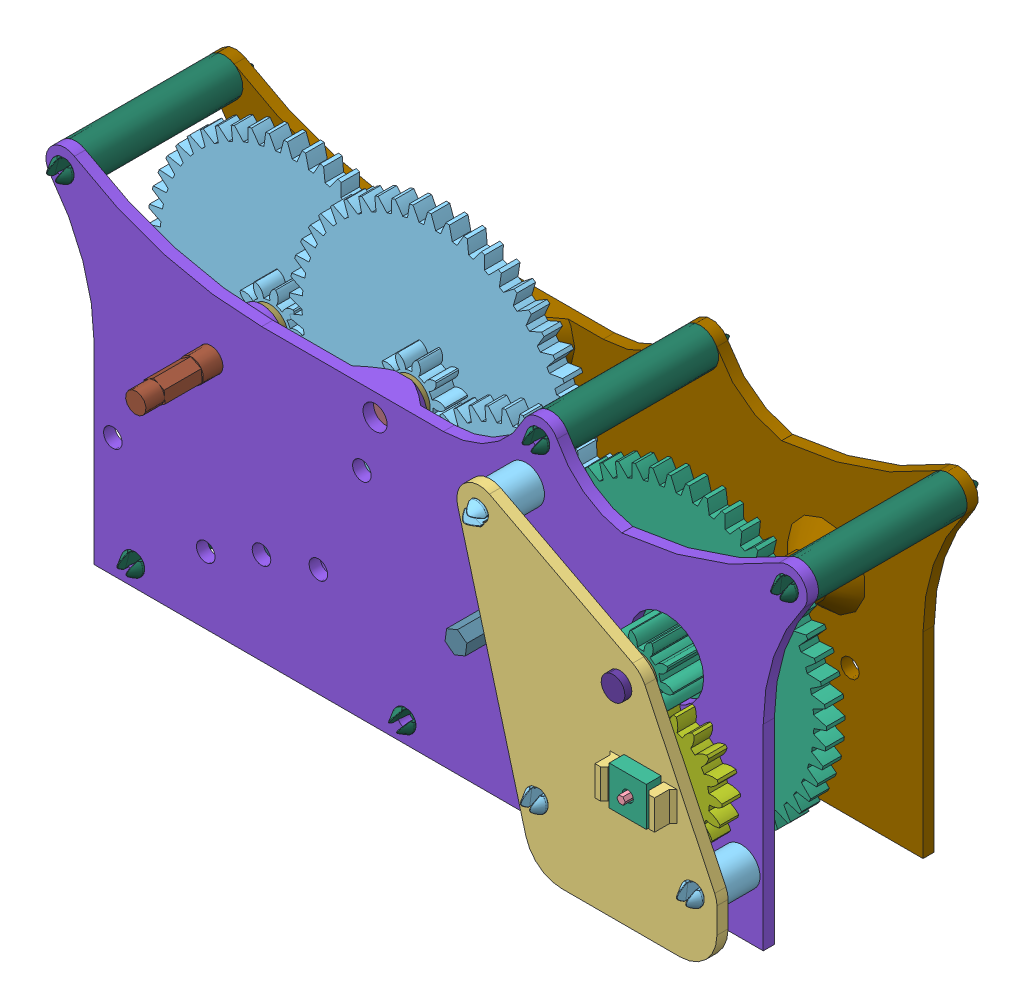
SolidWorks assembly gear_box_asm, configuration Default. Lengths in mm.
Overall size (222.79 131.64 101.4).
40 component instances, 24 part files, 110 mates.
Components (placement in the parent):
- motor_engagement-1: motor_engagement [Default] x (0.299774 -0.95401 0) z (0 0 1) size (23 23 4)
- engagement_adapter-1: engagement_adapter [Default] at (0 0 5) x (-0.299774 0.95401 0) z (-0.95401 -0.299774 0) size (25 21 25)
- metric_gear_10_hex-3: metric_gear_10_hex [Metric - Spur gear 1.5M 10T 20PA 12FW ---S10N75H50L5N] at (0 0 9) x (0 0 1) z (0.67631 0.736617 0) size (5 17.23 18)
- metric_gear_30_hex-2: metric_gear_30_hex [Metric - Spur gear 1.5M 33T 20PA 5FW ---S33N75H50L5N] at (30.3051 11.0301 14) x (0 0 -1) z (0.924711 -0.380669 0) size (11 52.42 52.48)
- metric_gear_50_hex-4: metric_gear_50_hex [Metric - Spur gear 1.5M 50T 20PA 5FW ---S50N75H50L5N] at (1.3796 45.5021 20) x (0 0 -1) z (-0.438763 -0.898603 0) size (11 77.9 78)
- metric_gear_50_hex-6: metric_gear_50_hex [Metric - Spur gear 1.5M 50T 20PA 5FW ---S50N75H50L5N] at (45.5529 54.0886 26) x (0 0 -1) z (-0.450414 -0.89282 0) size (11 77.9 78)
- metric_gear_50_hex-7: metric_gear_50_hex [Metric - Spur gear 1.5M 50T 20PA 5FW ---S50N75H50L5N] at (80.5244 25.7691 32) x (0 0 -1) z (-0.383635 0.923485 0) size (11 77.9 78)
- metric_gear_50_hex_extralong-7: metric_gear_50_hex_extralong [Metric - Spur gear 1.5M 50T 20PA 5FW ---S50N75H50L5N] at (123.9911 37.416 38) x (0 0 -1) z (0.962925 0.269769 0) size (16.2 77.9 78)
- metric_gear_19_hex-8: metric_gear_19_hex [Metric - Spur gear 1.5M 19T 20PA 5FW ---S19N75H50L5N] at (130.3502 16.6164 49.2) x (0 0 -1) z (-0.050856 0.998706 0) size (5 31.34 31.45)
- back_side-1: back_side [Default] at (0 0 39) size (204.87 94.29 19.7)
- front_side-2: front_side [Default] at (0 0 -4) size (204.87 94.29 34.7)
- engagement_support-1: engagement_support [Default] at (0 0 15) size (36.78 28.08 3)
- long_axle-1: long_axle [Default] at (1.3796 45.5021 7.8) x (-0.829281 -0.558831 0) z (0 0 1) size (10 10 54.4)
- small_washer-1: small_washer [Default] at (1.3796 45.5021 26.2) size (10 10 2)
- small_axle-2: small_axle [Default] at (45.5529 54.0886 13.8) x (0.567604 -0.823302 0) z (0 0 1) size (10 10 25.4)
- small_washer-2: small_washer [Default] at (45.5529 54.0886 34.2) x (-0.878181 -0.478329 0) z (0 0 -1) size (10 10 2)
- fourth_stage_axle-1: fourth_stage_axle [Default] at (80.5244 25.7691 19.8) x (-0.79398 0.607944 0) z (0 0 1) size (10 10 35.4)
- small_axle-4: small_axle [Default] at (30.3051 11.0301 1.8) x (0.792025 0.610489 0) z (0 0 1) size (10 10 25.4)
- small_washer-4: small_washer [Default] at (30.3051 11.0301 20.2) x (0.994715 0.102676 0) z (0 0 1) size (10 10 2)
- snap_fastner-1: snap_fastner [Default] at (156.8716 70.2965 -1) x (0 0 -1) z (0.991152 -0.132733 0) size (53.67 10 10)
- snap_fastner-2: snap_fastner [Default] at (90 71.2935 -1) x (0 0 -1) z (0.953456 -0.301532 0) size (53.67 10 10)
- snap_fastner-3: snap_fastner [Default] at (-38 70.2305 -1) x (0 0 -1) z (0.96799 -0.250988 0) size (53.67 10 10)
- snap_fastner-4: snap_fastner [Default] at (-19 -12 -1) x (0 0 -1) z (0.96799 -0.250988 0) size (53.67 10 10)
- snap_fastner-5: snap_fastner [Default] at (54 -12 -1) x (0 0 -1) z (0.853652 -0.520844 0) size (53.67 10 10)
- snap_fastner-6: snap_fastner [Default] at (116 -12 -1) x (0 0 -1) z (0.853652 -0.520844 0) size (53.67 10 10)
- snap_fastner_short-1: snap_fastner_short [Default] at (-17.3843 6.3274 -1) x (0 0 -1) z (0.97154 0.236875 0) size (29.67 7.5 7.5)
- snap_fastner_short-2: snap_fastner_short [Default] at (11.8916 -14.1718 -1) x (0 0 -1) z (0.935775 0.352597 0) size (29.67 7.5 7.5)
- fifth_stage_axle-1: fifth_stage_axle [Default] at (123.9911 37.416 25.8) x (0.968802 -0.247836 0) z (0 0 1) size (10 10 30.6)
- motor-1: motor [Default] at (0 0 -6) x (0 1 0) z (0 0 -1) size (24 18 42)
- motor_support-1: motor_support [Default] at (0 -12 -36.2) size (39.4 22 35.2)
- snap_fastner_motor-1: snap_fastner_motor [Default] at (-16.2 -2 -10) x (0 0 -1) z (0.97154 0.236875 0) size (19.67 7.5 7.5)
- snap_fastner_motor-2: snap_fastner_motor [Default] at (16.2 -2 -10) x (0 0 -1) z (0.999999 -0.001115 0) size (19.67 7.5 7.5)
- output_support-1: output_support [Default] at (144.1487 -1.1316 51.6) size (70 82.87 8)
- pot_axle-1: pot_axle [Default] at (130.3502 16.6164 39) x (0.543396 -0.839477 0) z (0 0 1) size (10 10 21.6)
- small_washer-5: small_washer [Default] at (123.9911 37.416 51.4) x (-0.878181 -0.478329 0) z (0 0 -1) size (10 10 2)
- small_washer-6: small_washer [Default] at (130.3502 16.6164 51.4) x (-0.878181 -0.478329 0) z (0 0 -1) size (10 10 2)
- output_snap_fastner-1: output_snap_fastner [Default] at (144.1487 -1.1316 42) x (0 0 -1) z (0.99268 -0.120771 0) size (23.27 10 10)
- output_snap_fastner-2: output_snap_fastner [Default] at (102.1487 -0.2026 42) x (0 0 -1) z (0.99268 -0.120771 0) size (23.27 10 10)
- output_snap_fastner-3: output_snap_fastner [Default] at (86.1487 58.8684 42) x (0 0 -1) z (0.438758 0.898605 0) size (23.27 10 10)
- pot_simplified-1: pot_simplified [Default] at (125.3502 11.3664 54.8) x (1 0 0) z (0 -1 0) size (10 4 10.5)
Mates (geometry in assembly coordinates):
- Coincident1: coincident anti-aligned: plane of motor_engagement-1 through (0 0 0) normal (0 0 -1)
- Concentric2: concentric: cylinder of motor_engagement-1 through (0 0 0) axis (0 0 1) radius 2
- Concentric3: concentric anti-aligned: cylinder of motor_engagement-1 through (0 0 4) axis (0 0 -1) radius 11.5; cylinder of engagement_adapter-1 through (0 0 4) axis (0 0 1) radius 12.5
- Parallel1: parallel aligned: plane of motor_engagement-1 through (4.6475 3.5568 4) normal (0.95401 0.299774 0); plane of engagement_adapter-1 through (9.6 0.9725 -2) normal (0.95401 0.299774 0)
- Parallel2: parallel anti-aligned: plane of engagement_adapter-1 through (0 0 6) normal (0 0 1); plane of metric_gear_10_hex-3 through (0 0 7) normal (0 0 -1)
- Coincident3: coincident aligned: plane of metric_gear_10_hex-3 through (0 0 14) normal (0 0 1); plane of metric_gear_30_hex-2 through (30.3051 11.0301 14) normal (0 0 1)
- Parallel3: parallel anti-aligned: plane of engagement_adapter-1 through (-3.5298 -1.1092 13) normal (-0.67631 -0.736617 0); plane of metric_gear_10_hex-3 through (-3.5775 -1.1242 59.0003) normal (0.67631 0.736617 0)
- Parallel4: parallel anti-aligned: plane of engagement_adapter-1 through (-0.8044 -3.6115 13) normal (0.299774 -0.95401 0); plane of metric_gear_10_hex-3 through (-0.8152 -3.6603 59.0003) normal (-0.299774 0.95401 0)
- Concentric4: concentric anti-aligned: cylinder of engagement_adapter-1 through (0 0 4) axis (0 0 1) radius 12.5; circle of metric_gear_10_hex-1
- Concentric5: concentric aligned: circle of metric_gear_30_hex-1
- Coincident5: coincident anti-aligned: plane of motor_engagement-1 through (0 0 4) normal (0 0 1); plane of engagement_adapter-1 through (0 0 4) normal (0 0 -1)
- GearMate2: gear = 33 : 10 mm: circle of metric_gear_10_hex-1; circle of metric_gear_30_hex-1
- Concentric6: concentric anti-aligned: circle of metric_gear_30_hex-1; cylinder of metric_gear_50_hex-5 through (30.3051 11.0301 35.6013) axis (0 0 -1) radius 35.624
- Coincident6: coincident aligned: plane of metric_gear_30_hex-2 through (27.335 8.7408 -36.0001) normal (0.991158 0.132687 0); plane of metric_gear_50_hex-5 through (32.278 12.5656 80.6014) normal (-0.37634 -0.926481 0)
- Coincident7: coincident aligned: plane of metric_gear_30_hex-2 through (28.1536 8.2393 20) normal (0 0 1); plane of metric_gear_50_hex-4 through (1.3796 45.5021 20) normal (0 0 1)
- Concentric7: concentric aligned: circle of spur gear_am-4
- GearMate3: gear = 10 : 50 mm: circle of spur gear_am-4; circle of metric_gear_30_hex-1
- Coincident8: coincident aligned: plane of metric_gear_50_hex-4 through (-1.2686 47.8269 26) normal (0 0 1); plane of metric_gear_50_hex-6 through (45.5529 54.0886 26) normal (0 0 1)
- Concentric8: concentric aligned: circle of metric_gear_50_hex-2
- GearMate4: gear = 10 : 50 mm: circle of metric_gear_50_hex-2; circle of metric_gear_50_hex-1
- Concentric9: concentric aligned: circle of metric_gear_50_hex-3
- Coincident9: coincident aligned: plane of metric_gear_50_hex-6 through (42.9351 56.4476 32) normal (0 0 1); plane of metric_gear_50_hex-7 through (80.5244 25.7691 32) normal (0 0 1)
- GearMate5: gear = 10 : 50 mm: circle of metric_gear_50_hex-3; circle of metric_gear_50_hex-2
- Coincident10: coincident aligned: plane of metric_gear_50_hex-7 through (84.0197 26.2172 38) normal (0 0 1); plane of metric_gear_50_hex_extralong-7 through (123.9911 37.416 38) normal (0 0 1)
- Concentric10: concentric aligned: circle of metric_gear_50_hex-4
- GearMate6: gear = 50 : 10 mm: circle of metric_gear_50_hex-3; circle of metric_gear_50_hex-4
- Concentric11: concentric aligned: circle of spur gear_am-5
- Concentric12: concentric anti-aligned: cylinder of engagement_adapter-1 through (0 0 4) axis (0 0 1) radius 12.5; cylinder of back_side-1 through (0 0 42) axis (0 0 -1) radius 2.5
- Parallel5: parallel aligned: plane of back_side-1 through (0 0 39) normal (0 1 0)
- Distance1: distance = 1 mm anti-aligned: plane of metric_gear_50_hex_extralong-7 through (123.9911 37.416 38) normal (0 0 1); plane of back_side-1 through (0 0 39) normal (0 0 -1)
- Coincident11: coincident aligned: plane of metric_gear_50_hex_extralong-7 through (124.0155 33.8922 49.2) normal (0 0 1); plane of metric_gear_19_hex-8 through (130.3502 16.6164 49.2) normal (0 0 1)
- GearMate7: gear = 19 : 10 mm: circle of metric_gear_50_hex_extralong-1; circle of metric_gear_19_hex-1
- Parallel6: parallel anti-aligned: plane of back_side-1 through (0 0 39) normal (0 0 -1); plane of front_side-2 through (0 0 -1) normal (0 0 1)
- Distance2: distance = 1 mm anti-aligned: plane of motor_engagement-1 through (0 0 0) normal (0 0 -1); plane of front_side-2 through (0 0 -1) normal (0 0 1)
- Concentric14: concentric anti-aligned: cylinder of engagement_adapter-1 through (0 0 4) axis (0 0 1) radius 12.5; cylinder of front_side-2 through (0 0 -1) axis (0 0 -1) radius 4
- Parallel7: parallel aligned: plane of back_side-1 through (-30 60 42) normal (0 1 0); plane of front_side-2 through (-30 60 -1) normal (0 1 0)
- Concentric15: concentric aligned: cylinder of engagement_adapter-1 through (0 0 19) axis (0 0 -1) radius 3.2043; cylinder of engagement_support-1 through (0 0 18) axis (0 0 -1) radius 3.25
- Parallel8: parallel aligned: plane of front_side-2 through (-30 -18 -1) normal (0 -1 0); plane of engagement_support-1 through (-10.1779 -18 18) normal (0 -1 0)
- Coincident12: coincident anti-aligned: plane of engagement_adapter-1 through (0 0 13) normal (0 0 1); plane of engagement_support-1 through (-17.3843 6.3274 13) normal (0 0 -1)
- Concentric16: concentric anti-aligned: cylinder of front_side-2 through (1.3796 45.5021 -4) axis (0 0 1) radius 2.5; cylinder of long_axle-1 through (1.3796 45.5021 12.8) axis (0 0 -1) radius 3.75
- Parallel9: parallel anti-aligned: plane of metric_gear_50_hex-4 through (4.7494 43.8568 -30.0001) normal (-0.558831 0.829281 0); plane of long_axle-1 through (1.6361 41.8111 26.2) normal (0.558831 -0.829281 0)
- Distance3: distance = 0.2 mm anti-aligned: plane of metric_gear_50_hex-4 through (1.3796 45.5021 15) normal (0 0 -1); plane of small_axle-1 through (1.3796 45.5021 14.8) normal (0 0 1)
- Coincident13: coincident anti-aligned: plane of long_axle-1 through (1.3796 45.5021 26.2) normal (0 0 1); plane of small_washer-1 through (1.3796 45.5021 26.2) normal (0 0 -1)
- Concentric17: concentric aligned: cylinder of long_axle-1 through (1.3796 45.5021 47.2) axis (0 0 -1) radius 3.2043; cylinder of small_washer-1 through (1.3796 45.5021 28.2) axis (0 0 -1) radius 3.2476
- Concentric18: concentric anti-aligned: cylinder of front_side-2 through (45.5529 54.0886 -4) axis (0 0 1) radius 2.5; cylinder of small_axle-2 through (45.5529 54.0886 18.8) axis (0 0 -1) radius 3.75
- Distance5: distance = 0.2 mm anti-aligned: plane of metric_gear_50_hex-6 through (45.5529 54.0886 21) normal (0 0 -1); plane of small_axle-2 through (45.5529 54.0886 20.8) normal (0 0 1)
- Concentric19: concentric anti-aligned: cylinder of small_axle-2 through (45.5529 54.0886 39.2) axis (0 0 -1) radius 3.2043; cylinder of small_washer-2 through (45.5529 54.0886 32.2) axis (0 0 1) radius 3.2476
- Coincident15: coincident anti-aligned: plane of small_axle-2 through (45.5529 54.0886 32.2) normal (0 0 1); plane of small_washer-2 through (45.5529 54.0886 32.2) normal (0 0 -1)
- Concentric20: concentric anti-aligned: circle of front_side-2; cylinder of fourth_stage_axle-1 through (80.5244 25.7691 24.8) axis (0 0 -1) radius 3.75
- Distance6: distance = 0.2 mm anti-aligned: plane of metric_gear_50_hex-7 through (80.5244 25.7691 27) normal (0 0 -1); plane of small_axle-3 through (80.5244 25.7691 26.8) normal (0 0 1)
- Parallel10: parallel anti-aligned: plane of metric_gear_50_hex-7 through (81.0101 29.4876 -18.0001) normal (-0.607944 -0.79398 0); plane of fourth_stage_axle-1 through (83.9413 27.1886 38.2) normal (0.607944 0.79398 0)
- Concentric211: concentric aligned: cylinder of fourth_stage_axle-1 through (80.5244 25.7691 45.2) axis (0 0 -1) radius 3.2043; cylinder of small_washer-3 through (80.5244 25.7691 40.2) axis (0 0 -1) radius 5
- Coincident171: coincident anti-aligned: plane of small_axle-3 through (80.5244 25.7691 45.4) normal (0 0 1); plane of small_washer-3 through (80.5244 25.7691 45.4) normal (0 0 -1)
- Coincident18: coincident anti-aligned: plane of fourth_stage_axle-1 through (80.5244 25.7691 38.2) normal (0 0 1); plane of small_washer-3 through (80.5244 25.7691 38.2) normal (0 0 -1)
- Concentric22: concentric anti-aligned: cylinder of front_side-2 through (30.3051 11.0301 -4) axis (0 0 1) radius 2.5; cylinder of small_axle-4 through (30.3051 11.0301 27.2) axis (0 0 -1) radius 3.2043
- Parallel11: parallel aligned: plane of metric_gear_30_hex-2 through (33.2752 13.3195 -36.0001) normal (-0.991158 -0.132687 0); plane of small_axle-4 through (26.8837 12.4386 20.2) normal (-0.991158 -0.132687 0)
- Distance7: distance = 0.2 mm anti-aligned: plane of metric_gear_30_hex-2 through (30.3051 11.0301 9) normal (0 0 -1); plane of small_axle-4 through (30.3051 11.0301 8.8) normal (0 0 1)
- Concentric231: concentric aligned: cylinder of small_axle-4 through (30.3051 11.0301 27.2) axis (0 0 -1) radius 3.2043; cylinder of small_washer-4 through (30.3051 11.0301 22.2) axis (0 0 -1) radius 5
- Coincident19: coincident anti-aligned: plane of small_axle-4 through (30.3051 11.0301 20.2) normal (0 0 1); plane of small_washer-4 through (30.3051 11.0301 20.2) normal (0 0 -1)
- Concentric232: concentric anti-aligned: circle of front_side-2; cylinder of snap_fastner-1 through (156.8716 70.2965 19) axis (0 0 -1) radius 5
- Coincident172: coincident anti-aligned: plane of front_side-2 through (0 0 -1) normal (0 0 1); plane of snap_fastner-1 through (156.8716 70.2965 -1) normal (0 0 -1)
- Concentric233: concentric anti-aligned: cylinder of back_side-1 through (90 71.2935 39) axis (0 0 1) radius 2.5; cylinder of snap_fastner-2 through (90 71.2935 19) axis (0 0 -1) radius 5
- Coincident173: coincident anti-aligned: plane of front_side-2 through (0 0 -1) normal (0 0 1); plane of snap_fastner-2 through (90 71.2935 -1) normal (0 0 -1)
- Concentric234: concentric anti-aligned: cylinder of front_side-2 through (-38 70.2305 -4) axis (0 0 1) radius 2.5; cylinder of snap_fastner-3 through (-38 70.2305 19) axis (0 0 -1) radius 5
- Coincident174: coincident anti-aligned: plane of front_side-2 through (0 0 -1) normal (0 0 1); plane of snap_fastner-3 through (-38 70.2305 -1) normal (0 0 -1)
- Concentric235: concentric anti-aligned: cylinder of front_side-2 through (-19 -12 -11) axis (0 0 1) radius 2.5; cylinder of snap_fastner-4 through (-19 -12 19) axis (0 0 -1) radius 5
- Coincident175: coincident anti-aligned: plane of front_side-2 through (0 0 -1) normal (0 0 1); plane of snap_fastner-4 through (-19 -12 -1) normal (0 0 -1)
- Concentric236: concentric anti-aligned: cylinder of front_side-2 through (54 -12 -11) axis (0 0 1) radius 2.5; cylinder of snap_fastner-5 through (54 -12 19) axis (0 0 -1) radius 5
- Coincident176: coincident anti-aligned: plane of front_side-2 through (0 0 -1) normal (0 0 1); plane of snap_fastner-5 through (54 -12 -1) normal (0 0 -1)
- Concentric237: concentric anti-aligned: cylinder of front_side-2 through (116 -12 -11) axis (0 0 1) radius 2.5; cylinder of snap_fastner-6 through (116 -12 19) axis (0 0 -1) radius 5
- Coincident177: coincident anti-aligned: plane of front_side-2 through (0 0 -1) normal (0 0 1); plane of snap_fastner-6 through (116 -12 -1) normal (0 0 -1)
- Concentric238: concentric anti-aligned: cylinder of front_side-2 through (-17.3843 6.3274 -4) axis (0 0 1) radius 2.5; cylinder of snap_fastner_short-1 through (-17.3843 6.3274 7) axis (0 0 -1) radius 3.75
- Coincident178: coincident anti-aligned: plane of front_side-2 through (0 0 -1) normal (0 0 1); plane of snap_fastner_short-1 through (-17.3843 6.3274 -1) normal (0 0 -1)
- Concentric239: concentric anti-aligned: cylinder of front_side-2 through (11.8916 -14.1718 -4) axis (0 0 1) radius 2.5; cylinder of snap_fastner_short-2 through (11.8916 -14.1718 7) axis (0 0 -1) radius 3.75
- Coincident179: coincident anti-aligned: plane of front_side-2 through (0 0 -1) normal (0 0 1); plane of snap_fastner_short-2 through (11.8916 -14.1718 -1) normal (0 0 -1)
- Parallel12: parallel anti-aligned: plane of metric_gear_50_hex_extralong-7 through (120.3581 38.3454 -12.0001) normal (0.715089 -0.699033 0); plane of fifth_stage_axle-1 through (122.993 40.9788 49.4) normal (-0.715089 0.699033 0)
- Concentric240: concentric anti-aligned: circle of back_side-1; cylinder of fifth_stage_axle-1 through (123.9911 37.416 30.8) axis (0 0 -1) radius 3.75
- Distance8: distance = 0.2 mm anti-aligned: plane of fifth_stage_axle-1 through (123.9911 37.416 32.8) normal (0 0 1); plane of metric_gear_50_hex_extralong-7 through (123.9911 37.416 33) normal (0 0 -1)
- Concentric241: concentric anti-aligned: cylinder of front_side-2 through (0 0 -1) axis (0 0 -1) radius 4; cylinder of motor-1 through (0 0 0) axis (0 0 1) radius 3.5
- Coincident180: coincident anti-aligned: plane of engagement_adapter-1 through (0 0 4) normal (0 0 -1); plane of motor-1 through (0 0 4) normal (0 0 1)
- Parallel13: parallel aligned: plane of motor-1 through (9 0 -6) normal (1 0 0)
- Parallel15: parallel aligned: plane of motor_support-1 through (-9.2 -12 -4) normal (0 1 0)
- Distance9: distance = 0.2 mm anti-aligned: plane of motor_support-1 through (-9.2 4 -4) normal (1 0 0); plane of motor-1 through (-9 0 -6) normal (-1 0 0)
- Coincident181: coincident anti-aligned: plane of front_side-2 through (0 0 -4) normal (0 0 -1); plane of motor_support-1 through (0 -12 -4) normal (0 0 1)
- Tangent1: tangent: circle of motor-1; plane of motor_support-1 through (-9.2 -12 -4) normal (0 1 0)
- Concentric242: concentric aligned: cylinder of front_side-2 through (-16.2 -2 30.7) axis (0 0 -1) radius 2.5; cylinder of snap_fastner_motor-1 through (-16.2 -2 -7) axis (0 0 -1) radius 3.75
- Coincident182: coincident anti-aligned: plane of front_side-2 through (0 0 -4) normal (0 0 -1); plane of snap_fastner_motor-1 through (-16.2 -2 -4) normal (0 0 1)
- Concentric243: concentric aligned: cylinder of front_side-2 through (16.2 -2 30.7) axis (0 0 -1) radius 2.5; cylinder of snap_fastner_motor-2 through (16.2 -2 -7) axis (0 0 -1) radius 3.75
- Coincident183: coincident anti-aligned: plane of front_side-2 through (0 0 -4) normal (0 0 -1); plane of snap_fastner_motor-2 through (16.2 -2 -4) normal (0 0 1)
- Concentric244: concentric anti-aligned: cylinder of back_side-1 through (144.1487 -1.1316 22.3) axis (0 0 1) radius 2.5; cylinder of output_support-1 through (144.1487 -1.1316 54.6) axis (0 0 -1) radius 2.5
- Concentric245: concentric anti-aligned: circle of back_side-1; cylinder of output_support-1 through (86.1487 58.8684 54.6) axis (0 0 -1) radius 2.5
- Concentric246: concentric anti-aligned: cylinder of back_side-1 through (130.3502 16.6164 39) axis (0 0 1) radius 3.8; cylinder of pot_axle-1 through (130.3502 16.6164 42) axis (0 0 -1) radius 3.75
- Coincident184: coincident anti-aligned: plane of back_side-1 through (0 0 42) normal (0 0 1); plane of pot_axle-1 through (130.3502 16.6164 42) normal (0 0 -1)
- Parallel16: parallel anti-aligned: plane of metric_gear_19_hex-8 through (128.3124 19.7644 -0.8001) normal (0.050856 -0.998706 0); plane of pot_axle-1 through (132.0348 19.9106 49.4) normal (-0.050856 0.998706 0)
- Concentric247: concentric anti-aligned: cylinder of fifth_stage_axle-1 through (123.9911 37.416 56.4) axis (0 0 -1) radius 3.2043; cylinder of small_washer-5 through (123.9911 37.416 49.4) axis (0 0 1) radius 3.2476
- Coincident185: coincident anti-aligned: plane of fifth_stage_axle-1 through (123.9911 37.416 49.4) normal (0 0 1); plane of small_washer-5 through (123.9911 37.416 49.4) normal (0 0 -1)
- Concentric248: concentric anti-aligned: cylinder of pot_axle-1 through (130.3502 16.6164 54.6) axis (0 0 -1) radius 3.2043; cylinder of small_washer-6 through (130.3502 16.6164 49.4) axis (0 0 1) radius 3.2476
- Coincident186: coincident anti-aligned: plane of pot_axle-1 through (130.3502 16.6164 49.4) normal (0 0 1); plane of small_washer-6 through (130.3502 16.6164 49.4) normal (0 0 -1)
- Distance10: distance = 0.2 mm anti-aligned: plane of small_washer-5 through (123.9911 37.416 51.4) normal (0 0 1); plane of output_support-1 through (86.1487 58.8684 51.6) normal (0 0 -1)
- Concentric249: concentric aligned: cylinder of output_support-1 through (144.1487 -1.1316 54.6) axis (0 0 -1) radius 2.5; cylinder of output_snap_fastner-1 through (144.1487 -1.1316 46.8) axis (0 0 -1) radius 5
- Coincident187: coincident anti-aligned: plane of back_side-1 through (0 0 42) normal (0 0 1); plane of output_snap_fastner-1 through (144.1487 -1.1316 42) normal (0 0 -1)
- Concentric250: concentric aligned: cylinder of output_support-1 through (102.1487 -0.2026 54.6) axis (0 0 -1) radius 2.5; cylinder of output_snap_fastner-2 through (102.1487 -0.2026 46.8) axis (0 0 -1) radius 5
- Coincident188: coincident anti-aligned: plane of back_side-1 through (0 0 42) normal (0 0 1); plane of output_snap_fastner-2 through (102.1487 -0.2026 42) normal (0 0 -1)
- Concentric251: concentric aligned: cylinder of output_support-1 through (86.1487 58.8684 54.6) axis (0 0 -1) radius 2.5; cylinder of output_snap_fastner-3 through (86.1487 58.8684 46.8) axis (0 0 -1) radius 5
- Coincident189: coincident anti-aligned: plane of back_side-1 through (0 0 42) normal (0 0 1); plane of output_snap_fastner-3 through (86.1487 58.8684 42) normal (0 0 -1)
- Concentric252: concentric aligned: circle of output_support-1; cylinder of pot_simplified-1 through (130.3502 16.6164 54.8) axis (0 0 1) radius 1.5
- Distance11: distance = 0.2 mm anti-aligned: plane of pot_simplified-1 through (125.3502 11.3664 54.8) normal (0 0 -1); plane of output_support-1 through (86.1487 58.8684 54.6) normal (0 0 1)
- Parallel17: parallel anti-aligned: plane of output_support-1 through (100.7531 -18 54.6) normal (0 -1 0); plane of pot_simplified-1 through (125.3502 21.8664 58.8) normal (0 1 0)
- Coincident190: coincident anti-aligned: plane of engagement_support-1 through (-17.3843 6.3274 15) normal (0 0 -1); plane of snap_fastner_short-1 through (-17.3843 6.3274 15) normal (0 0 1)
- Distance13: distance = 15 mm aligned: plane of metric_gear_10_hex-3 through (0 0 14) normal (0 0 1); plane of front_side-2 through (0 0 -1) normal (0 0 1)
